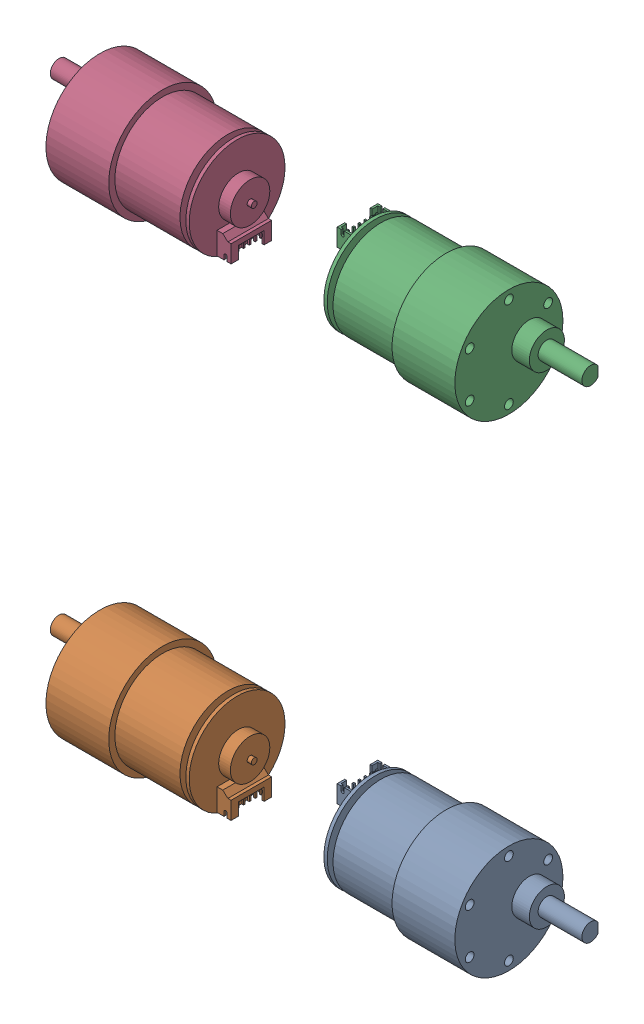
SolidWorks assembly Motors, configuration Varsayılan. Lengths in mm.
Overall size (182 202 37).
4 component instances, 4 part files, 0 mates.
Components (placement in the parent):
- DC Gear Motor 37mm_001-1: DC Gear Motor 37mm_001 [Varsayılan] at (79 -115.5 -28.5) x (0 0 -1) z (1 0 0) size (37 37 73.8)
- DC Gear Motor 37mm_002-1: DC Gear Motor 37mm_002 [Varsayılan] at (-79 -115.5 -28.5) x (0 0 -1) z (-1 0 0) size (37 37 73.8)
- DC Gear Motor 37mm_003-1: DC Gear Motor 37mm_003 [Varsayılan] at (79 49.5 -28.5) x (0 0 -1) z (1 0 0) size (37 37 73.8)
- DC Gear Motor 37mm_004-1: DC Gear Motor 37mm_004 [Varsayılan] at (-79 49.5 -28.5) x (0 0 -1) z (-1 0 0) size (37 37 73.8)
